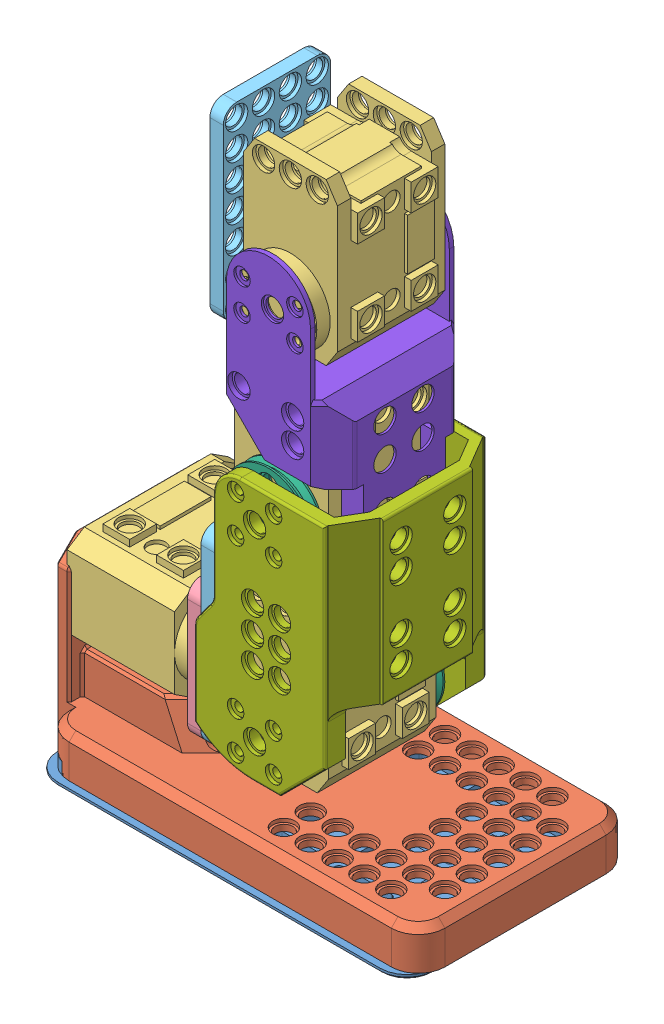
SolidWorks assembly feetAsm, configuration Default. Lengths in mm.
Overall size (87 141.68 49.5).
13 component instances, 8 part files, 47 mates.
Components (placement in the parent):
- sole-1: sole [Default] at origin size (84 4.06 48)
- foot-1: foot [Default] at (1 8.9 -1.5) x (0 0 1) z (-1 0 0) size (48 39 87)
- XL-1: XL [Default] at (-29.9431 31 -2) x (0 -1 0) z (1 0 0) size (24 36 27)
- cvt-1: cvt [Default] at (-14.9431 31 7.1) x (0 -1 0) z (0 0 1) size (30 3 18)
- SPD-1: SPD [Default] at (-10.4431 37 4.1) x (0 1 0) z (0 0 1) size (42 3 24)
- XL-2: XL [Default] at (3.0569 35 1.1) size (24 36 27)
- wheel-1: wheel [Default] at (3.0569 25.9 -13.15) x (0 1 0) z (-1 0 0) size (19 3 19)
- calf-1: calf [Default] at (11.7888 57.2246 1.1) x (0 0 1) z (0 -1 0) size (36 34.19 57.12)
- XL-3: XL [Default] at (3.0569 77 1.1) x (-1 0 0) z (0 0 -1) size (24 36 27)
- wheel-2: wheel [Default] at (3.0569 67.9 15.35) x (1 0 0) z (0 -1 0) size (19 3 19)
- ext_02-1: ext_02 [Default] at (16.0569 87.5 1.1) x (0 0 1) z (-1 0 0) size (32 58.53 24)
- XL-4: XL [Default] at (5.0569 118.6832 1.1) size (24 36 27)
- SPD-2: SPD [Default] at (-8.4431 120.6832 4.1) x (0 1 0) z (0 0 1) size (42 3 24)
Mates (geometry in assembly coordinates):
- Coincident1: coincident aligned: plane of sole-1 through (0 0 0) normal (0 0 1)
- Coincident2: coincident aligned: plane of sole-1 through (0 0 0) normal (0 1 0)
- Coincident3: coincident aligned: plane of sole-1 through (0 0 0) normal (1 0 0)
- Coincident4: coordinate: point of sole-1
- Parallel1: parallel aligned: plane of sole-1 through (0 0 0) normal (0 1 0); plane of foot-1 through (1 8.9 -1.5) normal (0 1 0)
- Parallel4: parallel anti-aligned: plane of sole-1 through (0 0 0) normal (1 0 0); plane of foot-1 through (1 8.9 -1.5) normal (-1 0 0)
- Concentric1: concentric aligned: circle of sole-1; circle of foot-1
- Coincident9: coincident anti-aligned: plane of sole-1 through (-36 1 -18) normal (0 1 0); plane of foot-1 through (-35 1 16.5) normal (0 -1 0)
- Parallel5: parallel anti-aligned: plane of foot-1 through (1 8.9 -1.5) normal (-1 0 0); plane of XL-1 through (-29.9431 31 -2) normal (1 0 0)
- Parallel6: parallel anti-aligned: plane of foot-1 through (1 8.9 -1.5) normal (0 1 0); plane of XL-1 through (-29.9431 31 -2) normal (0 -1 0)
- Concentric2: concentric aligned: cylinder of foot-1 through (-35.9431 19.8 -11) axis (0 -1 0) radius 2.5; cylinder of XL-1 through (-35.9431 19.8 -11) axis (0 -1 0) radius 2.5
- Coincident12: coincident anti-aligned: plane of foot-1 through (-35.9431 19.8 -11) normal (0 1 0); plane of XL-1 through (-35.9431 19.8 -11) normal (0 -1 0)
- Parallel7: parallel aligned: plane of XL-1 through (-29.9431 31 -2) normal (1 0 0); plane of cvt-1 through (-14.9431 31 7.1) normal (1 0 0)
- Parallel11: parallel anti-aligned: plane of XL-1 through (-29.9431 31 -2) normal (0 0 -1); plane of cvt-1 through (-14.9431 31 7.1) normal (0 0 1)
- Concentric3: concentric anti-aligned: circle of XL-1; circle of cvt-1
- Coincident17: coincident anti-aligned: plane of XL-1 through (-14.9431 31 7.1) normal (1 0 0); plane of cvt-1 through (-14.9431 19 13.1) normal (-1 0 0)
- Parallel12: parallel anti-aligned: plane of cvt-1 through (-14.9431 31 7.1) normal (1 0 0); plane of SPD-1 through (-10.4431 37 4.1) normal (-1 0 0)
- Parallel13: parallel anti-aligned: plane of cvt-1 through (-14.9431 31 7.1) normal (0 -1 0); plane of SPD-1 through (-10.4431 37 4.1) normal (0 1 0)
- Coincident21: coincident anti-aligned: circle of cvt-1; circle of SPD-1
- Parallel14: parallel anti-aligned: plane of SPD-1 through (-10.4431 37 4.1) normal (-1 0 0); plane of XL-2 through (3.0569 35 1.1) normal (1 0 0)
- Parallel15: parallel aligned: plane of SPD-1 through (-10.4431 37 4.1) normal (0 0 1); plane of XL-2 through (3.0569 35 1.1) normal (0 0 1)
- Coincident24: coincident anti-aligned: circle of SPD-1; circle of XL-2
- Parallel18: parallel anti-aligned: plane of XL-2 through (3.0569 35 1.1) normal (0 0 1); plane of wheel-1 through (3.0569 25.9 -13.15) normal (0 0 -1)
- Parallel19: parallel aligned: plane of XL-2 through (3.0569 35 1.1) normal (0 1 0); plane of wheel-1 through (3.0569 25.9 -13.15) normal (0 1 0)
- Coincident29: coincident aligned: circle of XL-2; circle of wheel-1
- Concentric5: concentric anti-aligned: circle of XL-2; circle of calf-1
- Parallel20: parallel anti-aligned: plane of XL-2 through (3.0569 35 1.1) normal (1 0 0); plane of calf-1 through (11.7888 57.2246 1.1) normal (-1 0 0)
- Parallel21: parallel anti-aligned: plane of XL-2 through (3.0569 35 1.1) normal (0 1 0); plane of calf-1 through (11.7888 57.2246 1.1) normal (0 -1 0)
- Coincident32: coincident anti-aligned: plane of XL-2 through (3.0569 25.9 16.1) normal (0 0 1); plane of calf-1 through (-10.3973 18.1059 16.1) normal (0 0 -1)
- Parallel22: parallel anti-aligned: plane of calf-1 through (11.7888 57.2246 1.1) normal (0 0 1); plane of XL-3 through (3.0569 77 1.1) normal (0 0 -1)
- Parallel23: parallel anti-aligned: plane of calf-1 through (11.7888 57.2246 1.1) normal (0 -1 0); plane of XL-3 through (3.0569 77 1.1) normal (0 1 0)
- Concentric6: concentric aligned: circle of calf-1; circle of XL-3
- Coincident35: coincident anti-aligned: plane of calf-1 through (-10.3973 18.1059 -13.9) normal (0 0 1); plane of XL-3 through (3.0569 67.9 -13.9) normal (0 0 -1)
- Parallel24: parallel anti-aligned: plane of XL-3 through (3.0569 77 1.1) normal (0 0 -1); plane of wheel-2 through (3.0569 67.9 15.35) normal (0 0 1)
- Parallel25: parallel anti-aligned: plane of XL-3 through (3.0569 77 1.1) normal (-1 0 0); plane of wheel-2 through (3.0569 67.9 15.35) normal (1 0 0)
- Coincident39: coincident aligned: circle of XL-3; circle of wheel-2
- Coincident42: coincident anti-aligned: plane of XL-3 through (3.0569 77 1.1) normal (0 0 -1); plane of ext_02-1 through (16.0569 87.5 1.1) normal (0 0 1)
- Parallel27: parallel aligned: plane of XL-3 through (3.0569 77 1.1) normal (0 1 0); plane of ext_02-1 through (16.0569 87.5 1.1) normal (0 1 0)
- Coincident44: coincident anti-aligned: plane of XL-3 through (-4.9431 95 -10.9) normal (0 1 0); plane of ext_02-1 through (-3.4431 95 -9.1033) normal (0 -1 0)
- Coincident45: coincident anti-aligned: plane of XL-3 through (13.5569 91.15 -10.9) normal (1 0 0); plane of ext_02-1 through (13.5569 87.5 1.1) normal (-1 0 0)
- Parallel30: parallel anti-aligned: plane of ext_02-1 through (16.0569 87.5 1.1) normal (-1 0 0); plane of XL-4 through (5.0569 118.6832 1.1) normal (1 0 0)
- Parallel31: parallel aligned: plane of ext_02-1 through (16.0569 87.5 1.1) normal (0 0 1); plane of XL-4 through (5.0569 118.6832 1.1) normal (0 0 1)
- Concentric8: concentric anti-aligned: circle of ext_02-1; circle of XL-4
- Coincident52: coincident anti-aligned: plane of ext_02-1 through (4.1479 110 16.1) normal (0 0 -1); plane of XL-4 through (5.0569 109.5832 16.1) normal (0 0 1)
- Parallel32: parallel anti-aligned: plane of XL-4 through (5.0569 118.6832 1.1) normal (1 0 0); plane of SPD-2 through (-8.4431 120.6832 4.1) normal (-1 0 0)
- Parallel33: parallel aligned: plane of XL-4 through (5.0569 118.6832 1.1) normal (0 1 0); plane of SPD-2 through (-8.4431 120.6832 4.1) normal (0 1 0)
- Coincident55: coincident anti-aligned: circle of XL-4; circle of SPD-2
